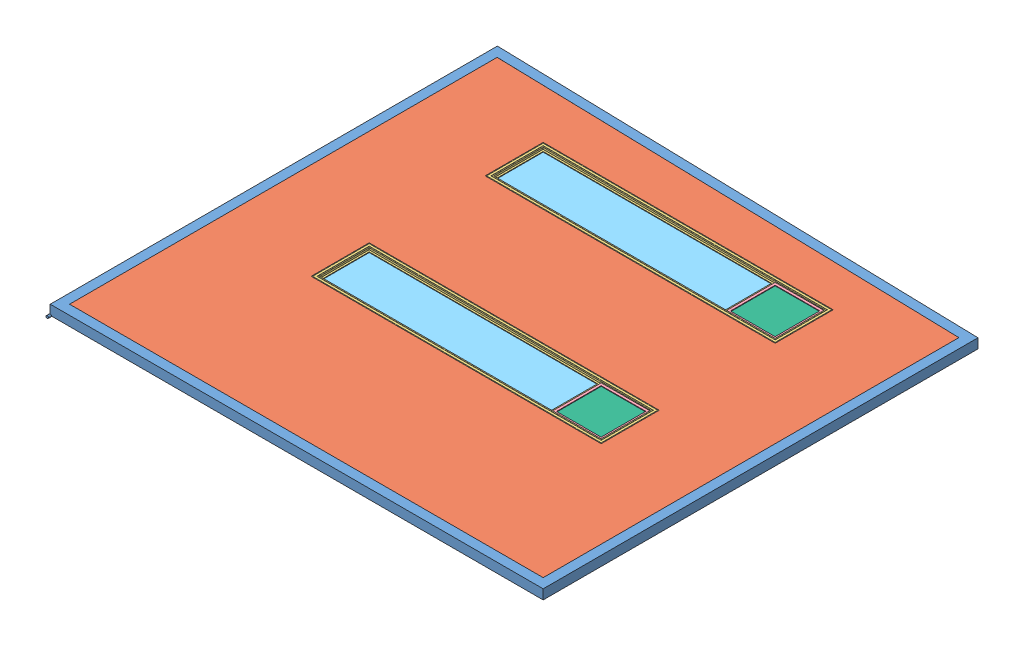
SolidWorks assembly EXAMPLE WALL, configuration Default. Lengths in mm.
Overall size (2597.15 57.15 2381.89).
16 component instances, 6 part files, 9 mates.
Components (placement in the parent):
- LS_WALL FRAME_100.38-1: LS_WALL FRAME_100.38 [Default] at (-1380.2718 1545.4483 3677.4348) size (2597.15 57.15 2381.89)
- LS WALL_INSULATION-1: LS WALL_INSULATION [Default] at (-109.9336 1520.0483 2528.7711) x (0 0 1) z (-1 0 0) size (2247.14 50.8 2489.2)
- 1050 WINDOW-1: 1050 WINDOW [Default] at (-714.5985 423.896 3552.0159) x (1 0 0) z (0 1 0) size (1524 304.8 44.45)
  - WINDOW MOLD-1: WINDOW MOLD [Default] at (629.7266 814.3811 1121.5523) size (1524 304.8 44.45)
  - SMALL WINDOW MOLD-1: SMALL WINDOW MOLD [Default] at (1239.3634 814.3811 1130.655) x (0.999995 0 0.003245) z (-0.003245 0 0.999995) size (260.35 260.35 19.05)
  - 1050 GLASS-1: 1050 GLASS [Default] at (500.3454 814.3811 1129.4898) size (1214.44 254 4.76)
  - 1050 GLASS-2: 1050 GLASS [Default] at (501.1961 813.5304 1121.5523) size (1214.44 254 4.76)
  - 1010 GLASS-1: 1010 GLASS [Default] at (1239.3376 814.3811 1138.5925) x (-0.999995 0 -0.003245) z (0.003245 0 -0.999995) size (241.3 241.3 4.76)
  - 1010 GLASS-2: 1010 GLASS [Default] at (1239.3634 814.3811 1130.655) x (-0.999995 0 -0.003245) z (0.003245 0 -0.999995) size (241.3 241.3 4.76)
- 1050 WINDOW-2: 1050 WINDOW [Default] at (-714.5985 423.896 2637.6159) x (1 0 0) z (0 1 0) size (1524 304.8 44.45)
  - WINDOW MOLD-1: WINDOW MOLD [Default] at (629.7266 814.3811 1121.5523) size (1524 304.8 44.45)
  - SMALL WINDOW MOLD-1: SMALL WINDOW MOLD [Default] at (1239.3634 814.3811 1130.655) x (0.999995 0 0.003245) z (-0.003245 0 0.999995) size (260.35 260.35 19.05)
  - 1050 GLASS-1: 1050 GLASS [Default] at (500.3454 814.3811 1129.4898) size (1214.44 254 4.76)
  - 1050 GLASS-2: 1050 GLASS [Default] at (501.1961 813.5304 1121.5523) size (1214.44 254 4.76)
  - 1010 GLASS-1: 1010 GLASS [Default] at (1239.3376 814.3811 1138.5925) x (-0.999995 0 -0.003245) z (0.003245 0 -0.999995) size (241.3 241.3 4.76)
  - 1010 GLASS-2: 1010 GLASS [Default] at (1239.3634 814.3811 1130.655) x (-0.999995 0 -0.003245) z (0.003245 0 -0.999995) size (241.3 241.3 4.76)
Mates (geometry in assembly coordinates):
- Coincident1: coincident anti-aligned: plane of LS_WALL FRAME_100.38-1 through (1134.3282 1570.8483 1414.8845) normal (-1 0 0); plane of LS WALL_INSULATION-1 through (1134.3282 1570.8483 1466.8728) normal (1 0 0)
- Coincident2: coincident anti-aligned: plane of LS_WALL FRAME_100.38-1 through (1187.7682 1570.8483 3652.0348) normal (0 0 -1); plane of LS WALL_INSULATION-1 through (1134.3282 1570.8483 3652.0348) normal (0 0 1)
- Coincident3: coincident aligned: plane of LS_WALL FRAME_100.38-1 through (1187.7682 1570.8483 3702.8348) normal (0 1 0); plane of LS WALL_INSULATION-1 through (-109.9336 1570.8483 2528.7711) normal (0 1 0)
- Coincident4: coincident anti-aligned: plane of LS_WALL FRAME_100.38-1 through (700.3492 1558.1483 1683.5348) normal (0 0 1); plane of 1050 WINDOW-2/WINDOW MOLD-1 through (-846.8718 1532.7483 1683.5348) normal (0 0 -1)
- Coincident5: coincident anti-aligned: plane of LS_WALL FRAME_100.38-1 through (700.3492 1558.1483 2597.9348) normal (0 0 1); plane of 1050 WINDOW-1/WINDOW MOLD-1 through (-846.8718 1532.7483 2597.9348) normal (0 0 -1)
- Coincident6: coincident anti-aligned: plane of LS_WALL FRAME_100.38-1 through (664.4282 1532.7483 1381.5511) normal (-1 0 0); plane of 1050 WINDOW-2/WINDOW MOLD-1 through (664.4282 1532.7483 1670.8348) normal (1 0 0)
- Coincident7: coincident: plane of LS_WALL FRAME_100.38-1 through (664.4282 1532.7483 1381.5511) normal (-1 0 0); line of 1050 WINDOW-1/WINDOW MOLD-1 through (664.4282 1532.7483 2597.9348) axis (0 0 1)
- Coincident8: coincident anti-aligned: plane of LS_WALL FRAME_100.38-1 through (664.4282 1558.1483 1381.5511) normal (0 1 0); plane of 1050 WINDOW-1/WINDOW MOLD-1 through (-846.8718 1558.1483 2597.9348) normal (0 -1 0)
- Coincident9: coincident anti-aligned: plane of LS_WALL FRAME_100.38-1 through (664.4282 1558.1483 1381.5511) normal (0 1 0); plane of 1050 WINDOW-2/WINDOW MOLD-1 through (-846.8718 1558.1483 1683.5348) normal (0 -1 0)
